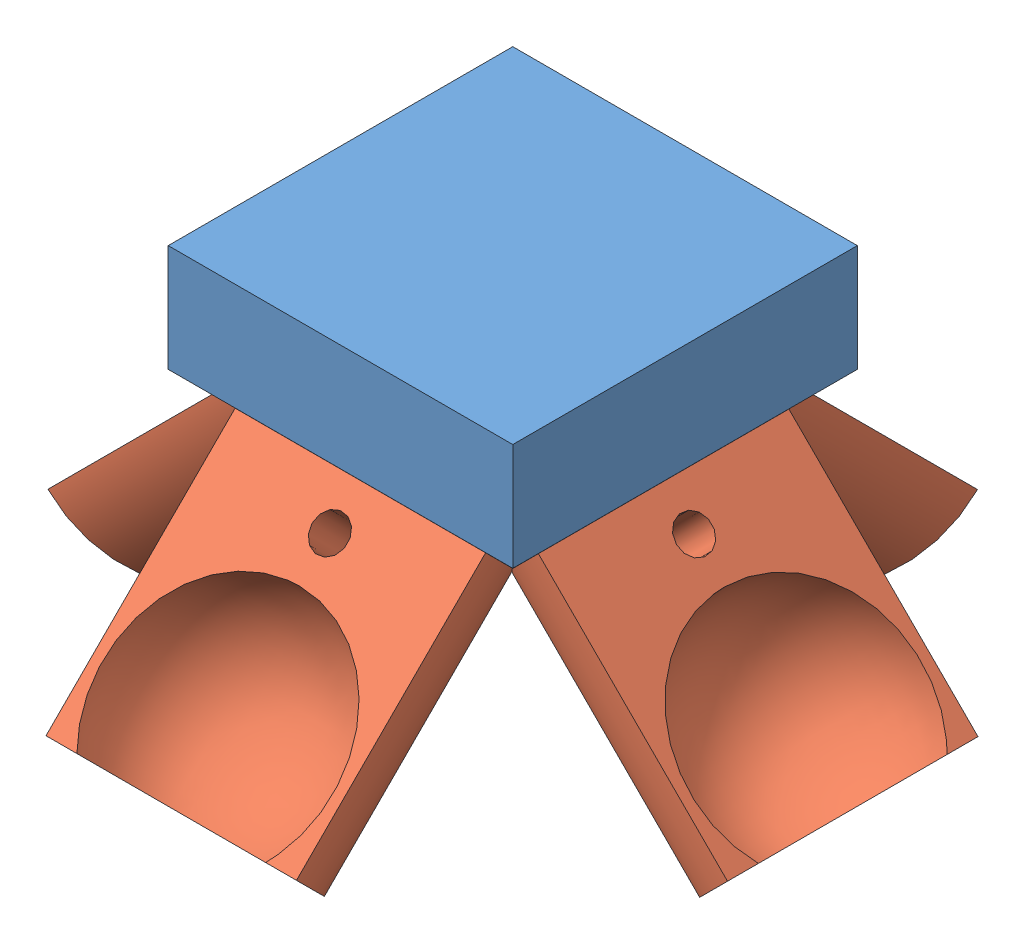
SolidWorks assembly Acople final, configuration Predeterminado. Lengths in mm.
Overall size (63.12 37.79 63.25).
5 component instances, 2 part files, 12 mates.
Components (placement in the parent):
- Base final-1: Base final [Predeterminado] at (22.7654 1.2928 32) size (32 22.43 32)
- Cilindro de base 4 puntos_6-1: Cilindro de base 4 puntos_6 [Predeterminado] at (-16.7159 -5.7926 20.8119) x (0 -0.707107 -0.707107) z (1 0 0) size (24.84 11.63 23.26)
- Cilindro de base 4 puntos_6-2: Cilindro de base 4 puntos_6 [Predeterminado] at (-43.918 -5.7769 48) x (-0.707107 -0.707107 0) z (0 0 -1) size (24.84 11.63 23.26)
- Cilindro de base 4 puntos_6-3: Cilindro de base 4 puntos_6 [Predeterminado] at (10.5151 -5.748 48) x (0.707107 -0.707107 0) z (0 0 1) size (24.84 11.63 23.26)
- Cilindro de base 4 puntos_6-4: Cilindro de base 4 puntos_6 [Predeterminado] at (-16.7159 -5.6015 75.3793) x (0 -0.707107 0.707107) z (-1 0 0) size (24.84 11.63 23.26)
Mates (geometry in assembly coordinates):
- Concéntrica2: concentric aligned: circle of Base final-1; circle of Cilindro de base 4 puntos_6-2
- Coincidente1: coincident anti-aligned: plane of Base final-1 through (-30.6951 7.446 48) normal (-0.707107 -0.707107 0); plane of Cilindro de base 4 puntos_6-2 through (-30.6951 7.446 59.6308) normal (0.707107 0.707107 0)
- Coincidente2: coincident aligned: plane of Base final-1 through (-30.6951 7.446 36.5904) normal (-0.707107 0.707107 0); plane of Cilindro de base 4 puntos_6-2 through (-12.9041 25.237 48) normal (-0.707107 0.707107 0)
- Coincidente3: coincident anti-aligned: plane of Base final-1 through (22.7654 -10.6211 43.9139) normal (0 -0.707107 0.707107); plane of Cilindro de base 4 puntos_6-4 through (-5.0852 7.6214 62.1564) normal (0 0.707107 -0.707107)
- Concéntrica3: concentric aligned: circle of Base final-1; circle of Cilindro de base 4 puntos_6-4
- Coincidente4: coincident aligned: plane of Base final-1 through (22.7654 7.6214 62.1564) normal (0 0.707107 0.707107); plane of Cilindro de base 4 puntos_6-4 through (-16.7159 25.4124 44.3654) normal (0 0.707107 0.707107)
- Concéntrica4: concentric aligned: circle of Base final-1; circle of Cilindro de base 4 puntos_6-1
- Coincidente5: coincident anti-aligned: plane of Base final-1 through (-16.7159 7.4303 34.0348) normal (0 -0.707107 -0.707107); plane of Cilindro de base 4 puntos_6-1 through (-28.3467 7.4303 34.0348) normal (0 0.707107 0.707107)
- Coincidente6: coincident aligned: plane of Base final-1 through (-5.3206 7.4303 34.0348) normal (0 0.707107 -0.707107); plane of Cilindro de base 4 puntos_6-1 through (-16.7159 25.2213 51.8258) normal (0 0.707107 -0.707107)
- Concéntrica5: concentric aligned: circle of Base final-1; circle of Cilindro de base 4 puntos_6-3
- Coincidente9: coincident anti-aligned: plane of Base final-1 through (-2.7078 7.4749 48) normal (0.707107 -0.707107 0); plane of Cilindro de base 4 puntos_6-3 through (-2.7078 7.4749 36.3692) normal (-0.707107 0.707107 0)
- Coincidente10: coincident aligned: plane of Base final-1 through (-2.7078 7.4749 59.4333) normal (0.707107 0.707107 0); plane of Cilindro de base 4 puntos_6-3 through (-20.4988 25.266 48) normal (0.707107 0.707107 0)
